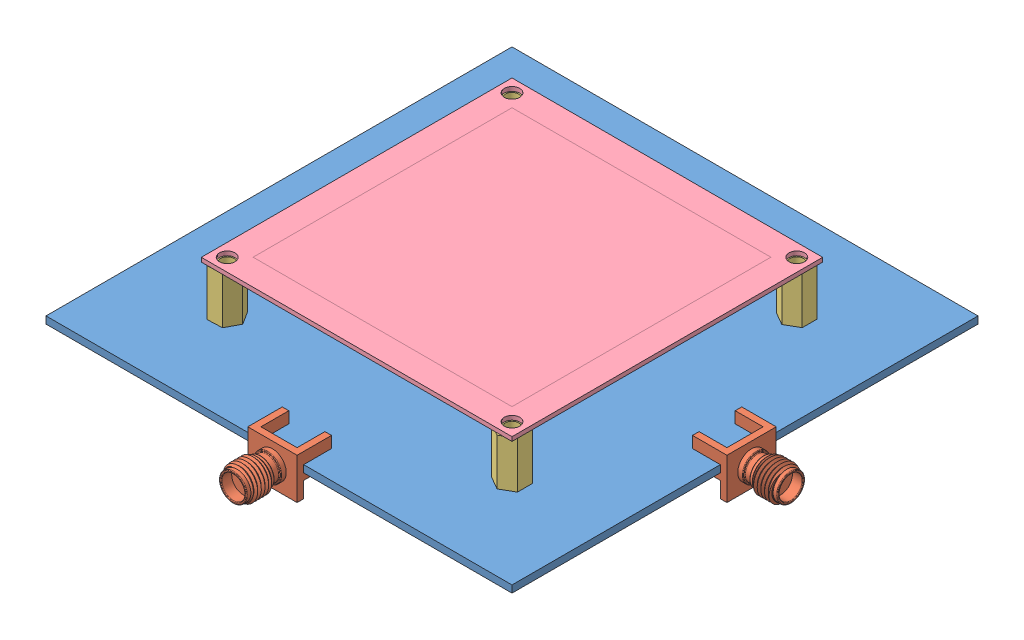
SolidWorks assembly pcb_assembly, configuration Default. Lengths in mm.
Overall size (98.89 15.53 98.89).
8 component instances, 4 part files, 18 mates.
Components (placement in the parent):
- pcb_lower-1: pcb_lower [Default] at origin size (90 1.39 90)
- Amphenol_132415-1: Amphenol_132415 [Default] at (0 -0.38 46.27) x (-1 0 0) z (0 0 1) size (9.52 7.92 14.27)
- Amphenol_132415-2: Amphenol_132415 [Default] at (46.27 -0.38 0) x (0 0 1) z (1 0 0) size (9.52 7.92 14.27)
- spacer-1: spacer [Default] at (-27.5 1.375 27.5) x (0.884323 0 0.466876) z (-0.466876 0 0.884323) size (5 9 5.77)
- spacer-2: spacer [Default] at (27.5 1.375 -27.5) size (5 9 5.77)
- spacer-3: spacer [Default] at (27.5 1.375 27.5) size (5 9 5.77)
- spacer-4: spacer [Default] at (-27.5 1.375 -27.5) size (5 9 5.77)
- pcb_upper-1: pcb_upper [Default] at (0 10.375 0) size (60 0.82 60)
Mates (geometry in assembly coordinates):
- Coincident1: coordinate: point of pcb_lower-1; point of assembly
- Coincident2: coincident anti-aligned: plane of pcb_lower-1 through (-45 1.375 45) normal (0 0 1); plane of Amphenol_132415-1 through (0 -0.38 45) normal (0 0 -1)
- Coincident4: coincident anti-aligned: plane of Amphenol_132415-1 through (0 -0.38 46.27) normal (-1 0 0); plane of assembly through (0 0 0) normal (1 0 0)
- Coincident5: coincident anti-aligned: plane of pcb_lower-1 through (45 1.375 -45) normal (1 0 0); plane of Amphenol_132415-2 through (45 -0.38 0) normal (-1 0 0)
- Coincident7: coincident aligned: plane of Amphenol_132415-2 through (46.27 -0.38 0) normal (0 0 1); plane of assembly through (0 0 0) normal (0 0 1)
- Coincident8: coincident aligned: plane of pcb_upper-1 through (0 10.375 0) normal (0 0 1); plane of assembly through (0 0 0) normal (0 0 1)
- Coincident9: coincident aligned: plane of pcb_upper-1 through (0 10.375 0) normal (1 0 0); plane of assembly through (0 0 0) normal (1 0 0)
- Coincident10: coincident anti-aligned: plane of spacer-1 through (-27.5 10.375 27.5) normal (0 1 0); plane of pcb_upper-1 through (0 10.375 0) normal (0 -1 0)
- Coincident11: coincident anti-aligned: plane of pcb_lower-1 through (0 1.375 0) normal (0 1 0); plane of spacer-1 through (-27.5 1.375 27.5) normal (0 -1 0)
- Concentric2: concentric aligned: cylinder of spacer-1 through (-27.5 10.375 27.5) axis (0 1 0) radius 1.25; cylinder of pcb_upper-1 through (-27.5 11.175 27.5) axis (0 1 0) radius 1.5
- Coincident12: coincident anti-aligned: plane of pcb_lower-1 through (0 1.375 0) normal (0 1 0); plane of spacer-4 through (-27.5 1.375 -27.5) normal (0 -1 0)
- Concentric3: concentric aligned: cylinder of spacer-4 through (-27.5 10.375 -27.5) axis (0 1 0) radius 1.25; cylinder of pcb_upper-1 through (-27.5 11.175 -27.5) axis (0 1 0) radius 1.5
- Concentric4: concentric aligned: cylinder of spacer-3 through (27.5 10.375 27.5) axis (0 1 0) radius 1.25; cylinder of pcb_upper-1 through (27.5 11.175 27.5) axis (0 1 0) radius 1.5
- Coincident13: coincident anti-aligned: plane of pcb_lower-1 through (0 1.375 0) normal (0 1 0); plane of spacer-3 through (27.5 1.375 27.5) normal (0 -1 0)
- Concentric5: concentric aligned: cylinder of spacer-2 through (27.5 10.375 -27.5) axis (0 1 0) radius 1.25; cylinder of pcb_upper-1 through (27.5 11.175 -27.5) axis (0 1 0) radius 1.5
- Coincident14: coincident anti-aligned: plane of pcb_lower-1 through (0 1.375 0) normal (0 1 0); plane of spacer-2 through (27.5 1.375 -27.5) normal (0 -1 0)
- Coincident15: coincident anti-aligned: plane of pcb_lower-1 through (0 0 0) normal (0 -1 0); plane of Amphenol_132415-1 through (0 0 46.27) normal (0 1 0)
- Coincident16: coincident anti-aligned: plane of pcb_lower-1 through (0 0 0) normal (0 -1 0); plane of Amphenol_132415-2 through (46.27 0 0) normal (0 1 0)
